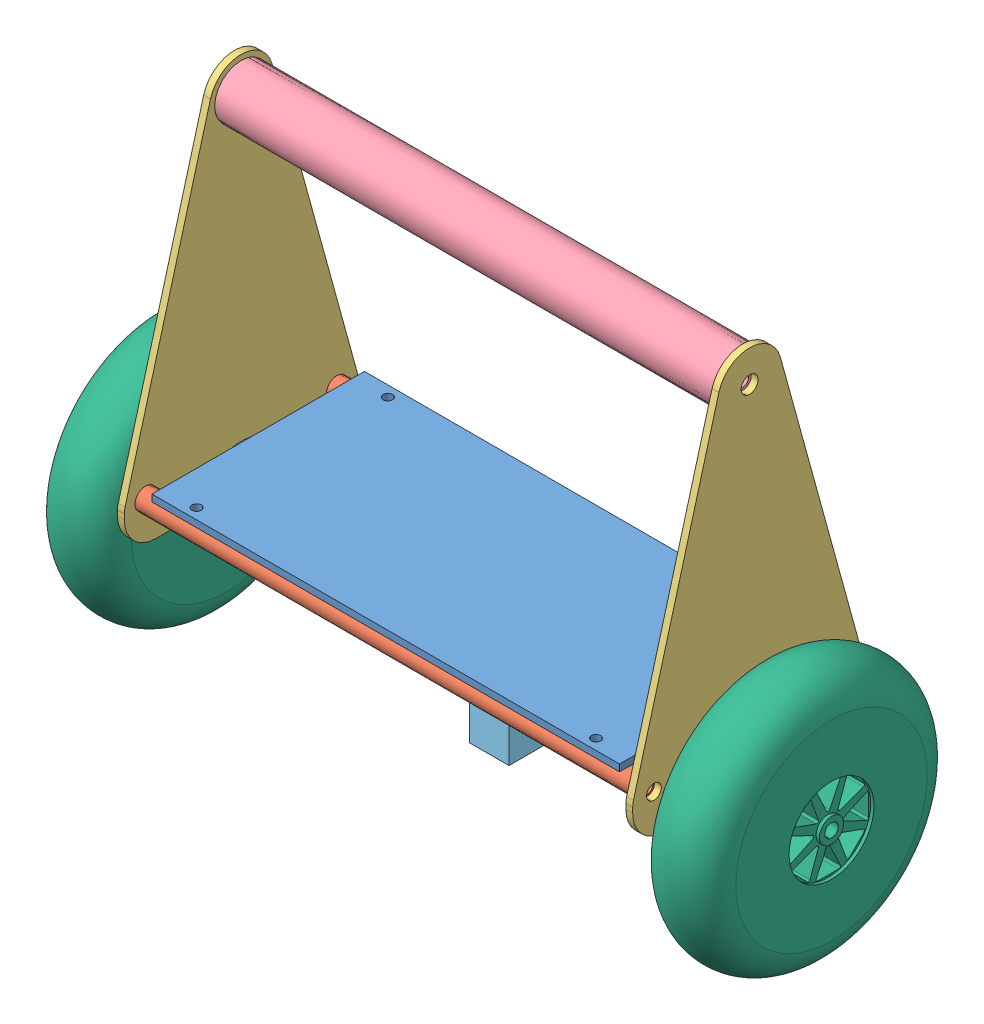
SolidWorks assembly Assembly, configuration Default. Lengths in mm.
Overall size (202.89 150.72 76.2).
10 component instances, 6 part files, 25 mates.
Components (placement in the parent):
- Base plate-1: Base plate [Default] at (-29.9276 95.6529 -49.4781) size (139.7 2.03 63.5)
- Base strut-1: Base strut [Default] at (45.0024 92.4779 -78.0531) x (0 0 -1) z (0 1 0) size (6.35 149.86 6.35)
- Base strut-2: Base strut [Default] at (-104.8576 92.4779 -20.9031) x (0 0 1) z (0 1 0) size (6.35 149.86 6.35)
- Side Plate-1: Side Plate [Default] at (47.0344 92.4779 -78.0531) x (0 0 1) z (-1 0 0) size (69.85 125.27 2.03)
- Side Plate-2: Side Plate [Default] at (-106.8896 92.4779 -20.9031) x (0 0 -1) z (1 0 0) size (69.85 125.27 2.03)
- Top Spar-1: Top Spar [Default] at (45.0024 183.5557 -49.4781) x (0 1 0) z (0 0 1) size (15.88 149.86 15.88)
- Motor-2: Motor [Default] at (-79.4576 80.5082 -49.4781) x (0 0 1) z (-1 0 0) size (31.5 24.89 74.93)
- Motor-3: Motor [Default] at (19.6024 80.5082 -49.4781) x (0 0 -1) z (1 0 0) size (31.5 24.89 74.93)
- Wheel-1: Wheel [Default] at (71.5174 80.461 -49.4781) x (0 0 -1) z (1 0 0) size (76.2 76.2 22.23)
- Wheel-2: Wheel [Default] at (-131.3726 80.461 -49.4781) x (0 0 1) z (-1 0 0) size (76.2 76.2 22.23)
Mates (geometry in assembly coordinates):
- Tangent1: tangent anti-aligned: plane of Base plate-1 through (-29.9276 95.6529 -49.4781) normal (0 -1 0); cylinder of Base strut-2 through (45.0024 92.4779 -20.9031) axis (-1 0 0) radius 3.175
- Concentric1: concentric aligned: cylinder of Base plate-1 through (-89.6176 95.6529 -20.9031) axis (0 1 0) radius 1.397; cylinder of Base strut-2 through (-89.6176 89.3029 -20.9031) axis (0 1 0) radius 1.1303
- Concentric2: concentric aligned: cylinder of Base plate-1 through (29.7624 95.6529 -20.9031) axis (0 1 0) radius 1.397; cylinder of Base strut-2 through (29.7624 89.3029 -20.9031) axis (0 1 0) radius 1.1303
- Tangent2: tangent anti-aligned: plane of Base plate-1 through (-29.9276 95.6529 -49.4781) normal (0 -1 0); cylinder of Base strut-1 through (-104.8576 92.4779 -78.0531) axis (1 0 0) radius 3.175
- Concentric4: concentric aligned: cylinder of Base plate-1 through (-89.6176 95.6529 -78.0531) axis (0 1 0) radius 1.397; cylinder of Base strut-1 through (-89.6176 89.3029 -78.0531) axis (0 1 0) radius 1.1303
- Concentric5: concentric aligned: cylinder of Base plate-1 through (29.7624 95.6529 -78.0531) axis (0 1 0) radius 1.397; cylinder of Base strut-1 through (29.7624 89.3029 -78.0531) axis (0 1 0) radius 1.1303
- Coincident1: coincident anti-aligned: plane of Base strut-1 through (45.0024 92.4779 -78.0531) normal (1 0 0); plane of Side Plate-1 through (45.0024 91.6207 -78.0531) normal (-1 0 0)
- Concentric7: concentric aligned: cylinder of Base strut-1 through (45.0024 92.4779 -78.0531) axis (1 0 0) radius 1.7272; cylinder of Side Plate-1 through (45.0024 92.4779 -78.0531) axis (1 0 0) radius 2.2225
- Concentric8: concentric aligned: cylinder of Base strut-2 through (45.0024 92.4779 -20.9031) axis (1 0 0) radius 1.7272; cylinder of Side Plate-1 through (45.0024 92.4779 -20.9031) axis (1 0 0) radius 2.2225
- Coincident2: coincident anti-aligned: plane of Base strut-1 through (-104.8576 92.4779 -78.0531) normal (-1 0 0); plane of Side Plate-2 through (-104.8576 91.6207 -20.9031) normal (1 0 0)
- Concentric9: concentric aligned: cylinder of Base strut-1 through (-104.8576 92.4779 -78.0531) axis (-1 0 0) radius 1.7272; cylinder of Side Plate-2 through (-104.8576 92.4779 -78.0531) axis (-1 0 0) radius 2.2225
- Concentric10: concentric aligned: cylinder of Base strut-2 through (-104.8576 92.4779 -20.9031) axis (-1 0 0) radius 1.7272; cylinder of Side Plate-2 through (-104.8576 92.4779 -20.9031) axis (-1 0 0) radius 2.2225
- Coincident3: coincident anti-aligned: plane of Side Plate-2 through (-104.8576 91.6207 -20.9031) normal (1 0 0); plane of Top Spar-1 through (-104.8576 183.5557 -49.4781) normal (-1 0 0)
- Concentric11: concentric aligned: cylinder of Side Plate-2 through (-104.8576 183.5557 -49.4781) axis (-1 0 0) radius 2.54; cylinder of Top Spar-1 through (-104.8576 183.5557 -49.4781) axis (-1 0 0) radius 1.7272
- Concentric12: concentric aligned: cylinder of Side Plate-1 through (45.0024 183.5557 -49.4781) axis (1 0 0) radius 2.54; cylinder of Top Spar-1 through (45.0024 183.5557 -49.4781) axis (1 0 0) radius 1.7272
- Coincident4: coincident anti-aligned: plane of Motor-2 through (-104.8576 80.5082 -49.4781) normal (-1 0 0); plane of Side Plate-2 through (-104.8576 91.6207 -20.9031) normal (1 0 0)
- Concentric13: concentric anti-aligned: cylinder of Motor-2 through (-107.3976 80.5082 -49.4781) axis (1 0 0) radius 3.5; cylinder of Side Plate-2 through (-104.8576 80.5082 -49.4781) axis (-1 0 0) radius 3.5
- Concentric14: concentric aligned: cylinder of Motor-2 through (-101.6826 74.4978 -55.4885) axis (-1 0 0) radius 1.5; cylinder of Side Plate-2 through (-104.8576 74.4978 -55.4885) axis (-1 0 0) radius 1.55
- Coincident13: coincident anti-aligned: plane of Side Plate-1 through (45.0024 91.6207 -78.0531) normal (-1 0 0); plane of Motor-3 through (45.0024 80.5082 -49.4781) normal (1 0 0)
- Concentric17: concentric anti-aligned: cylinder of Side Plate-1 through (45.0024 80.5082 -49.4781) axis (1 0 0) radius 3.5; cylinder of Motor-3 through (47.5424 80.5082 -49.4781) axis (-1 0 0) radius 3.5
- Concentric18: concentric aligned: cylinder of Side Plate-1 through (45.0024 74.4978 -55.4885) axis (1 0 0) radius 1.55; cylinder of Motor-3 through (41.8274 74.4978 -55.4885) axis (1 0 0) radius 1.5
- Concentric19: concentric aligned: cylinder of Motor-3 through (57.2924 80.461 -49.4781) axis (-1 0 0) radius 2.0339; cylinder of Wheel-1 through (49.2924 80.461 -49.4781) axis (-1 0 0) radius 2
- Coincident14: coincident anti-aligned: plane of Motor-3 through (49.2924 80.5082 -49.4781) normal (1 0 0); plane of Wheel-1 through (49.2924 109.036 -49.4781) normal (-1 0 0)
- Concentric20: concentric aligned: cylinder of Motor-2 through (-117.1476 80.461 -49.4781) axis (1 0 0) radius 2.0339; cylinder of Wheel-2 through (-109.1476 80.461 -49.4781) axis (1 0 0) radius 2
- Coincident15: coincident anti-aligned: plane of Motor-2 through (-109.1476 80.5082 -49.4781) normal (-1 0 0); plane of Wheel-2 through (-109.1476 109.036 -49.4781) normal (1 0 0)
